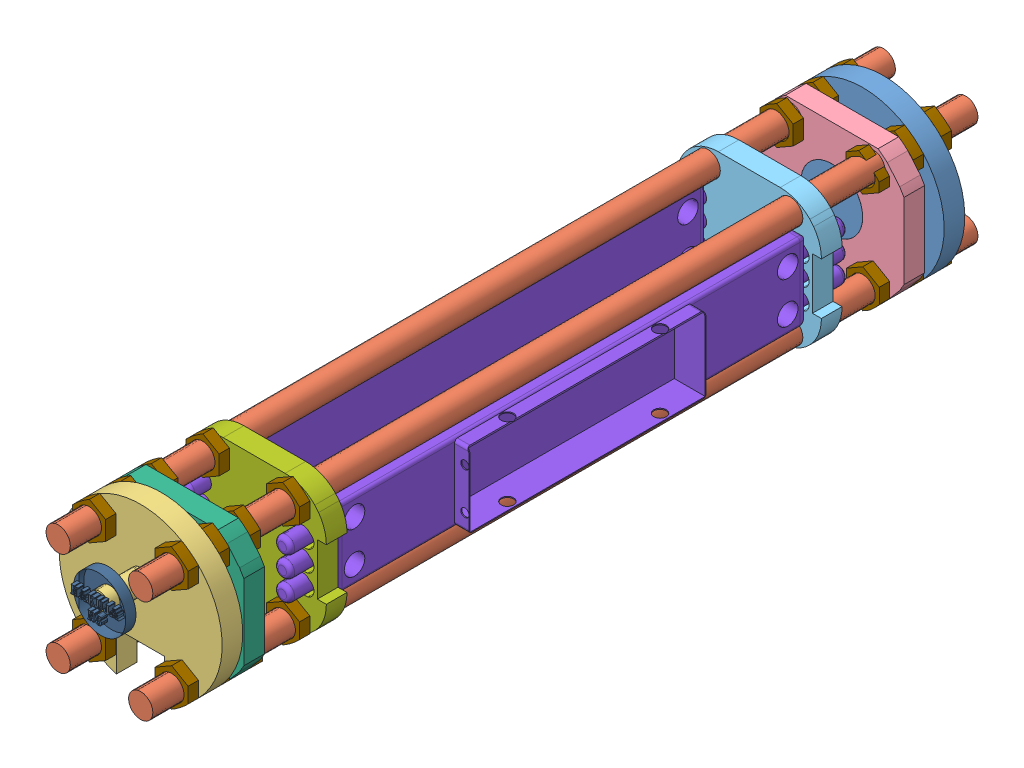
SolidWorks assembly Final_assemblyv2_v9_Fiberglass.step, configuration Default. Lengths in mm.
Overall size (79 77.25 403.33).
41 component instances, 10 part files, 0 mates.
Components (placement in the parent):
- Holder Avionics Bay.step-1: Holder Avionics Bay.step [Default] at origin size (79 77.25 25)
- holder_rod.step-1: holder_rod.step [Default] at (-20 -25 -20) size (11.8 11.8 400)
- holder_rod.step-2: holder_rod.step [Default] at (-20 25 -20) size (11.8 11.8 400)
- holder_rod.step-3: holder_rod.step [Default] at (20 -25 -20) size (11.8 11.8 400)
- holder_rod.step-4: holder_rod.step [Default] at (20 25 -20) size (11.8 11.8 400)
- Holder Avionics Bay v5(Mirror).step-1: Holder Avionics Bay v5(Mirror).step [Default] at (0 0 360) size (79 77.25 45)
- bottom compartment.step-1: bottom compartment.step [Default] at (0 0 15) size (70 65 10)
- Bottom coupler.step-1: Bottom coupler.step [Default] at (0 0 55) size (70 65 10)
- bottom compartment v11(Mirror).step-1: bottom compartment v11(Mirror).step [Default] at (0 0 345) size (70 65 10)
- Bottom coupler v4(Mirror).step-1: Bottom coupler v4(Mirror).step [Default] at (0 0 305) size (70 65 10)
- Ebay.step-1: Ebay.step [Default] at (-24.7152 -0.1039 65) x (0 -1 0) z (0 0 1) size (37.59 17.04 270)
- Ebay.step-2: Ebay.step [Default] at (23.6609 1.1098 65) x (0 1 0) z (0 0 1) size (37.59 17.04 270)
- holder_nut.step-1: holder_nut.step [Default] at (-19.7125 -25.3564 27) size (16 18.48 5)
- holder_nut.step-2: holder_nut.step [Default] at (22.0357 -23.0001 27) size (16 18.48 5)
- holder_nut.step-3: holder_nut.step [Default] at (21.9624 25.8778 27) size (16 18.48 5)
- holder_nut.step-4: holder_nut.step [Default] at (-19.7125 24.6436 27) size (16 18.48 5)
- holder_nut.step-5: holder_nut.step [Default] at (21.4998 -25.6594 10) size (16 18.48 5)
- holder_nut.step-6: holder_nut.step [Default] at (-19.7125 -25.3564 10) size (16 18.48 5)
- holder_nut.step-7: holder_nut.step [Default] at (-19.7125 25.6436 10) size (16 18.48 5)
- holder_nut.step-8: holder_nut.step [Default] at (21.4998 25.3406 10) size (16 18.48 5)
- holder_nut.step-9: holder_nut.step [Default] at (-20 25 305) size (16 18.48 5)
- holder_nut.step-10: holder_nut.step [Default] at (20 -25 306) size (16 18.48 5)
- holder_nut.step-11: holder_nut.step [Default] at (20 25 306) size (16 18.48 5)
- holder_nut.step-12: holder_nut.step [Default] at (20 -25 329) size (16 18.48 5)
- holder_nut.step-13: holder_nut.step [Default] at (-20 25 330) size (16 18.48 5)
- holder_nut.step-14: holder_nut.step [Default] at (-20 -25 305) size (16 18.48 5)
- holder_nut.step-15: holder_nut.step [Default] at (-20 -25 330) size (16 18.48 5)
- holder_nut.step-16: holder_nut.step [Default] at (-20 -25 345) size (16 18.48 5)
- holder_nut.step-17: holder_nut.step [Default] at (-20 25 345) size (16 18.48 5)
- holder_nut.step-18: holder_nut.step [Default] at (20 25 330) size (16 18.48 5)
- holder_nut.step-19: holder_nut.step [Default] at (20 25 345) size (16 18.48 5)
- holder_nut.step-20: holder_nut.step [Default] at (20 -25 345) size (16 18.48 5)
- holder_nut.step-21: holder_nut.step [Default] at (20 -25 360) size (16 18.48 5)
- holder_nut.step-22: holder_nut.step [Default] at (-20 -25 360) size (16 18.48 5)
- holder_nut.step-23: holder_nut.step [Default] at (-20 25 360) size (16 18.48 5)
- holder_nut.step-24: holder_nut.step [Default] at (20 25 360) size (16 18.48 5)
- holder_nut.step-25: holder_nut.step [Default] at (-20 25 0) x (1 0 0) z (0 0 -1) size (16 18.48 5)
- holder_nut.step-26: holder_nut.step [Default] at (20 25 0) x (1 0 0) z (0 0 -1) size (16 18.48 5)
- holder_nut.step-27: holder_nut.step [Default] at (20 -25 0) x (1 0 0) z (0 0 -1) size (16 18.48 5)
- holder_nut.step-28: holder_nut.step [Default] at (-20 -25 0) x (1 0 0) z (0 0 -1) size (16 18.48 5)
- assemblyv2.step-1: assemblyv2.step [Default] at origin size (25.28 25.75 8.33)
